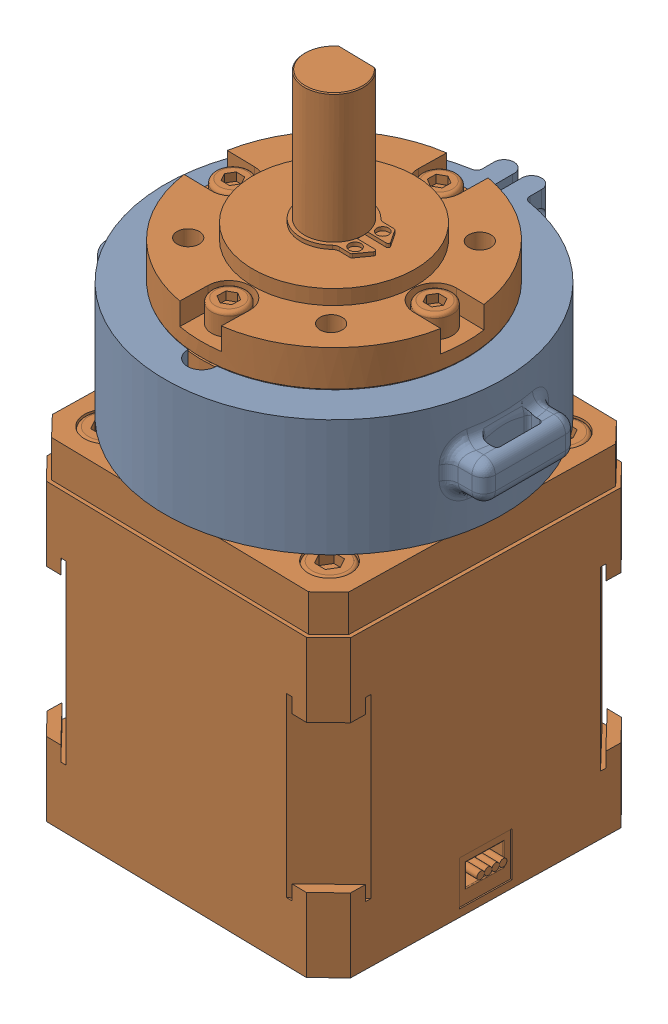
SolidWorks assembly 3-StepperandClamp, configuration Default. Lengths in mm.
Overall size (53.34 87.3 49.25).
2 component instances, 2 part files, 1 mates.
Components (placement in the parent):
- 3-SteppermotormountNew-1: 3-SteppermotormountNew [Default] at (-128.5327 11.5427 61.6662) size (53.34 15.88 49.25)
- 3-Nema17SW-1: 3-Nema17SW [Default] at (-128.5327 -2.8313 61.6662) x (0.999808 0 0.019579) z (0 1 0) size (42.88 42 87.3)
Mates (geometry in assembly coordinates):
- Concentric1: concentric: cylinder of assembly; cylinder of assembly; cylinder of 3-SteppermotormountNew-1 through (-128.5327 3.6052 61.6662) axis (0 1 0) radius 17.9546; cylinder of 3-Nema17SW-1 through (-128.5327 19.3437 61.6662) axis (0 -1 0) radius 18
